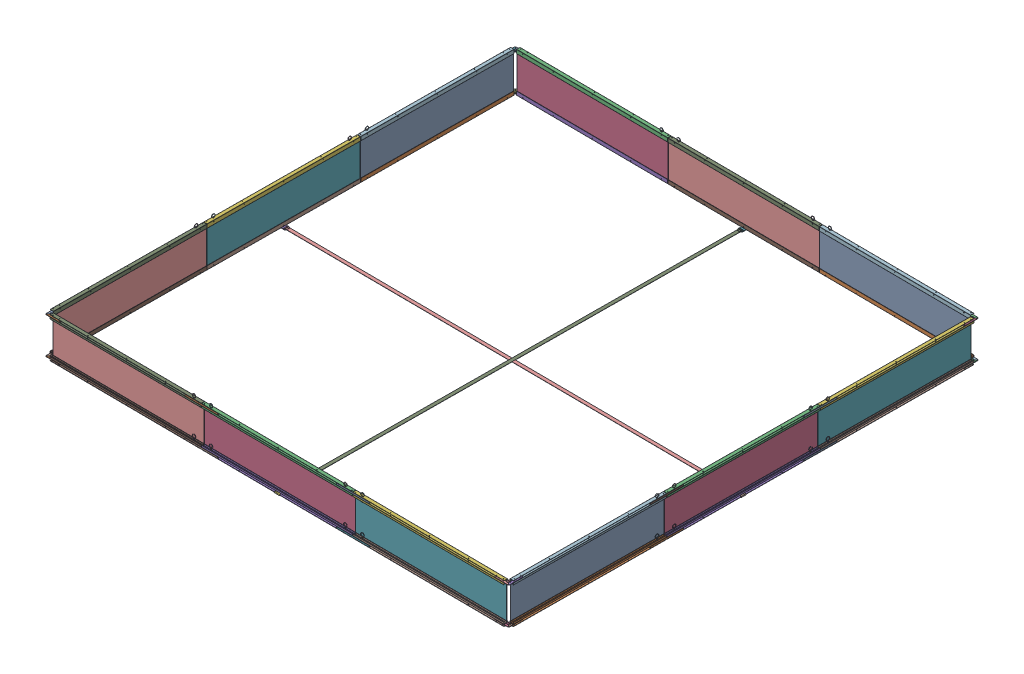
SolidWorks assembly FIELD_RelicRecovery_FTC Field Asm, configuration Default. Lengths in mm.
Overall size (3662.56 340.61 3662.56).
118 component instances, 8 part files, 0 mates.
Components (placement in the parent):
- FIELD_RelicRecovery_Corner Knife Hinge half-1: FIELD_RelicRecovery_Corner Knife Hinge half [Default] at (287.0747 134.4952 780.9902) x (-0.007115 0 0.999975) z (0.999975 0 0.007115) size (108.93 5.01 35.86)
- FIELD_RelicRecovery_Corner Knife Hinge half_DefaultSM-FLAT-PATTERN-1: FIELD_RelicRecovery_Corner Knife Hinge half_DefaultSM-FLAT-PATTERN [Default] at (348.7346 132.3362 843.5339) x (-0.999975 0 -0.007115) z (0.007115 0 -0.999975) size (108.93 5.01 35.86)
- FIELD_RelicRecovery_Corner Knife Hinge half_DefaultSM-FLAT-PATTERN-2: FIELD_RelicRecovery_Corner Knife Hinge half_DefaultSM-FLAT-PATTERN [Default] at (3867.9545 131.9552 -2749.2903) x (0.999975 0 0.007115) z (-0.007115 0 0.999975) size (108.93 5.01 35.86)
- FIELD_RelicRecovery_Corner Knife Hinge half-2: FIELD_RelicRecovery_Corner Knife Hinge half [Default] at (3929.6145 134.1142 -2686.7466) x (0.007115 0 -0.999975) z (-0.999975 0 -0.007115) size (108.93 5.01 35.86)
- FIELD_RelicRecovery_NewStrapClip-1: FIELD_RelicRecovery_NewStrapClip [Default] at (290.995 -150.588 -965.8349) x (-0.007115 0 0.999975) z (-0.999975 0 -0.007115) size (38.1 7.37 60.83)
- FIELD_RelicRecovery_Rail Final Asm-1: FIELD_RelicRecovery_Rail Final Asm [Default] at (207.932 -93.3892 -853.6445) x (0.007115 0 -0.999975) z (0.999975 0 0.007115) size (1185.42 310.9 27.05)
  - FIELD_RelicRecovery_NewRail-1: FIELD_RelicRecovery_NewRail [Default] at (-479.9559 232.0754 95.5976) size (1185.42 29.72 27.05)
  - FIELD_RelicRecovery_New FTC Side Glass-1: FIELD_RelicRecovery_New FTC Side Glass [Default] at (112.7531 85.1364 102.7604) size (1185.42 270.76 3)
  - FIELD_RelicRecovery_NewRail-2: FIELD_RelicRecovery_NewRail [Default] at (705.4621 -61.8026 95.5976) x (-1 0 0) z (0 0 1) size (1185.42 29.72 27.05)
- FIELD_RelicRecovery_Rail Final Asm-2: FIELD_RelicRecovery_Rail Final Asm [Default] at (1019.0407 -93.2622 939.0773) x (-0.999975 0 -0.007115) z (0.007115 0 -0.999975) size (1185.42 310.9 27.05)
  - FIELD_RelicRecovery_NewRail-1: FIELD_RelicRecovery_NewRail [Default] at (-479.9559 232.0754 95.5976) size (1185.42 29.72 27.05)
  - FIELD_RelicRecovery_New FTC Side Glass-1: FIELD_RelicRecovery_New FTC Side Glass [Default] at (112.7531 85.1364 102.7604) size (1185.42 270.76 3)
  - FIELD_RelicRecovery_NewRail-2: FIELD_RelicRecovery_NewRail [Default] at (705.4621 -61.8026 95.5976) x (-1 0 0) z (0 0 1) size (1185.42 29.72 27.05)
- FIELD_RelicRecovery_Rail Final Asm-3: FIELD_RelicRecovery_Rail Final Asm [Default] at (216.3891 -93.3892 -2042.1821) x (0.007115 0 -0.999975) z (0.999975 0 0.007115) size (1185.42 310.9 27.05)
  - FIELD_RelicRecovery_NewRail-1: FIELD_RelicRecovery_NewRail [Default] at (-479.9559 232.0754 95.5976) size (1185.42 29.72 27.05)
  - FIELD_RelicRecovery_New FTC Side Glass-1: FIELD_RelicRecovery_New FTC Side Glass [Default] at (112.7531 85.1364 102.7604) size (1185.42 270.76 3)
  - FIELD_RelicRecovery_NewRail-2: FIELD_RelicRecovery_NewRail [Default] at (705.4621 -61.8026 95.5976) x (-1 0 0) z (0 0 1) size (1185.42 29.72 27.05)
- FIELD_RelicRecovery_Rail Final Asm-4: FIELD_RelicRecovery_Rail Final Asm [Default] at (2207.5782 -93.2622 947.5344) x (-0.999975 0 -0.007115) z (0.007115 0 -0.999975) size (1185.42 310.9 27.05)
  - FIELD_RelicRecovery_NewRail-1: FIELD_RelicRecovery_NewRail [Default] at (-479.9559 232.0754 95.5976) size (1185.42 29.72 27.05)
  - FIELD_RelicRecovery_New FTC Side Glass-1: FIELD_RelicRecovery_New FTC Side Glass [Default] at (112.7531 85.1364 102.7604) size (1185.42 270.76 3)
  - FIELD_RelicRecovery_NewRail-2: FIELD_RelicRecovery_NewRail [Default] at (705.4621 -61.8026 95.5976) x (-1 0 0) z (0 0 1) size (1185.42 29.72 27.05)
- FIELD_RelicRecovery_Rail Final Asm-5: FIELD_RelicRecovery_Rail Final Asm [Default] at (3396.1157 -93.2622 955.9914) x (-0.999975 0 -0.007115) z (0.007115 0 -0.999975) size (1185.42 310.9 27.05)
  - FIELD_RelicRecovery_NewRail-1: FIELD_RelicRecovery_NewRail [Default] at (-479.9559 232.0754 95.5976) size (1185.42 29.72 27.05)
  - FIELD_RelicRecovery_New FTC Side Glass-1: FIELD_RelicRecovery_New FTC Side Glass [Default] at (112.7531 85.1364 102.7604) size (1185.42 270.76 3)
  - FIELD_RelicRecovery_NewRail-2: FIELD_RelicRecovery_NewRail [Default] at (705.4621 -61.8026 95.5976) x (-1 0 0) z (0 0 1) size (1185.42 29.72 27.05)
- FIELD_RelicRecovery_Rail Final Asm-6: FIELD_RelicRecovery_Rail Final Asm [Default] at (199.475 -93.3892 334.893) x (0.007115 0 -0.999975) z (0.999975 0 0.007115) size (1185.42 310.9 27.05)
  - FIELD_RelicRecovery_NewRail-1: FIELD_RelicRecovery_NewRail [Default] at (-479.9559 232.0754 95.5976) size (1185.42 29.72 27.05)
  - FIELD_RelicRecovery_New FTC Side Glass-1: FIELD_RelicRecovery_New FTC Side Glass [Default] at (112.7531 85.1364 102.7604) size (1185.42 270.76 3)
  - FIELD_RelicRecovery_NewRail-2: FIELD_RelicRecovery_NewRail [Default] at (705.4621 -61.8026 95.5976) x (-1 0 0) z (0 0 1) size (1185.42 29.72 27.05)
- FIELD_RelicRecovery_Rail Final Asm-7: FIELD_RelicRecovery_Rail Final Asm [Default] at (4000.3001 -93.2622 136.4257) x (-0.007115 0 0.999975) z (-0.999975 0 -0.007115) size (1185.42 310.9 27.05)
  - FIELD_RelicRecovery_NewRail-1: FIELD_RelicRecovery_NewRail [Default] at (-479.9559 232.0754 95.5976) size (1185.42 29.72 27.05)
  - FIELD_RelicRecovery_New FTC Side Glass-1: FIELD_RelicRecovery_New FTC Side Glass [Default] at (112.7531 85.1364 102.7604) size (1185.42 270.76 3)
  - FIELD_RelicRecovery_NewRail-2: FIELD_RelicRecovery_NewRail [Default] at (705.4621 -61.8026 95.5976) x (-1 0 0) z (0 0 1) size (1185.42 29.72 27.05)
- FIELD_RelicRecovery_Rail Final Asm-8: FIELD_RelicRecovery_Rail Final Asm [Default] at (4008.7571 -93.5162 -1052.1118) x (-0.007115 0 0.999975) z (-0.999975 0 -0.007115) size (1185.42 310.9 27.05)
  - FIELD_RelicRecovery_NewRail-1: FIELD_RelicRecovery_NewRail [Default] at (-479.9559 232.0754 95.5976) size (1185.42 29.72 27.05)
  - FIELD_RelicRecovery_New FTC Side Glass-1: FIELD_RelicRecovery_New FTC Side Glass [Default] at (112.7531 85.1364 102.7604) size (1185.42 270.76 3)
  - FIELD_RelicRecovery_NewRail-2: FIELD_RelicRecovery_NewRail [Default] at (705.4621 -61.8026 95.5976) x (-1 0 0) z (0 0 1) size (1185.42 29.72 27.05)
- FIELD_RelicRecovery_Rail Final Asm-9: FIELD_RelicRecovery_Rail Final Asm [Default] at (4017.2141 -93.7702 -2240.6493) x (-0.007115 0 0.999975) z (-0.999975 0 -0.007115) size (1185.42 310.9 27.05)
  - FIELD_RelicRecovery_NewRail-1: FIELD_RelicRecovery_NewRail [Default] at (-479.9559 232.0754 95.5976) size (1185.42 29.72 27.05)
  - FIELD_RelicRecovery_New FTC Side Glass-1: FIELD_RelicRecovery_New FTC Side Glass [Default] at (112.7531 85.1364 102.7604) size (1185.42 270.76 3)
  - FIELD_RelicRecovery_NewRail-2: FIELD_RelicRecovery_NewRail [Default] at (705.4621 -61.8026 95.5976) x (-1 0 0) z (0 0 1) size (1185.42 29.72 27.05)
- FIELD_RelicRecovery_Rail Final Asm-10: FIELD_RelicRecovery_Rail Final Asm [Default] at (2009.1109 -93.3892 -2853.2907) x (0.999975 0 0.007115) z (-0.007115 0 0.999975) size (1185.42 310.9 27.05)
  - FIELD_RelicRecovery_NewRail-1: FIELD_RelicRecovery_NewRail [Default] at (-479.9559 232.0754 95.5976) size (1185.42 29.72 27.05)
  - FIELD_RelicRecovery_New FTC Side Glass-1: FIELD_RelicRecovery_New FTC Side Glass [Default] at (112.7531 85.1364 102.7604) size (1185.42 270.76 3)
  - FIELD_RelicRecovery_NewRail-2: FIELD_RelicRecovery_NewRail [Default] at (705.4621 -61.8026 95.5976) x (-1 0 0) z (0 0 1) size (1185.42 29.72 27.05)
- FIELD_RelicRecovery_Rail Final Asm-11: FIELD_RelicRecovery_Rail Final Asm [Default] at (3197.6485 -93.6432 -2844.8337) x (0.999975 0 0.007115) z (-0.007115 0 0.999975) size (1185.42 310.9 27.05)
  - FIELD_RelicRecovery_NewRail-1: FIELD_RelicRecovery_NewRail [Default] at (-479.9559 232.0754 95.5976) size (1185.42 29.72 27.05)
  - FIELD_RelicRecovery_New FTC Side Glass-1: FIELD_RelicRecovery_New FTC Side Glass [Default] at (112.7531 85.1364 102.7604) size (1185.42 270.76 3)
  - FIELD_RelicRecovery_NewRail-2: FIELD_RelicRecovery_NewRail [Default] at (705.4621 -61.8026 95.5976) x (-1 0 0) z (0 0 1) size (1185.42 29.72 27.05)
- FIELD_RelicRecovery_Rail Final Asm-12: FIELD_RelicRecovery_Rail Final Asm [Default] at (820.5734 -93.3892 -2861.7477) x (0.999975 0 0.007115) z (-0.007115 0 0.999975) size (1185.42 310.9 27.05)
  - FIELD_RelicRecovery_NewRail-1: FIELD_RelicRecovery_NewRail [Default] at (-479.9559 232.0754 95.5976) size (1185.42 29.72 27.05)
  - FIELD_RelicRecovery_New FTC Side Glass-1: FIELD_RelicRecovery_New FTC Side Glass [Default] at (112.7531 85.1364 102.7604) size (1185.42 270.76 3)
  - FIELD_RelicRecovery_NewRail-2: FIELD_RelicRecovery_NewRail [Default] at (705.4621 -61.8026 95.5976) x (-1 0 0) z (0 0 1) size (1185.42 29.72 27.05)
- FIELD_RelicRecovery_NewStrapClip-2: FIELD_RelicRecovery_NewStrapClip [Default] at (2095.4386 -150.461 864.4718) x (0.999975 0 0.007115) z (-0.007115 0 0.999975) size (38.1 7.37 60.83)
- FIELD_RelicRecovery_NewStrapClip-3: FIELD_RelicRecovery_NewStrapClip [Default] at (2121.3013 -150.588 -2770.2278) x (-0.999975 0 -0.007115) z (0.007115 0 -0.999975) size (38.1 7.37 60.83)
- FIELD_RelicRecovery_NewStrapClip-4: FIELD_RelicRecovery_NewStrapClip [Default] at (3925.6945 -150.715 -939.9722) x (0.007115 0 -0.999975) z (0.999975 0 0.007115) size (38.1 7.37 60.83)
- FIELD_RelicRecovery_Corner Knife Hinge half-3: FIELD_RelicRecovery_Corner Knife Hinge half [Default] at (311.9325 -151.0008 -2712.4881) x (0.007115 0 -0.999975) z (0.999975 0 0.007115) size (108.93 5.01 35.86)
- FIELD_RelicRecovery_Corner Knife Hinge half-4: FIELD_RelicRecovery_Corner Knife Hinge half [Default] at (3842.213 134.6222 868.3917) x (0.999975 0 0.007115) z (0.007115 0 -0.999975) size (108.93 5.01 35.86)
- FIELD_RelicRecovery_Corner Knife Hinge half-5: FIELD_RelicRecovery_Corner Knife Hinge half [Default] at (3904.7567 -150.7468 806.7318) x (-0.007115 0 0.999975) z (-0.999975 0 -0.007115) size (108.93 5.01 35.86)
- FIELD_RelicRecovery_Corner Knife Hinge half-6: FIELD_RelicRecovery_Corner Knife Hinge half [Default] at (3867.9545 -151.2548 -2749.2903) x (0.999975 0 0.007115) z (-0.007115 0 0.999975) size (108.93 5.01 35.86)
- FIELD_RelicRecovery_Corner Knife Hinge half-7: FIELD_RelicRecovery_Corner Knife Hinge half [Default] at (374.4762 134.3682 -2774.1481) x (-0.999975 0 -0.007115) z (-0.007115 0 0.999975) size (108.93 5.01 35.86)
- FIELD_RelicRecovery_Corner Knife Hinge half-8: FIELD_RelicRecovery_Corner Knife Hinge half [Default] at (348.7346 -150.8738 843.5339) x (-0.999975 0 -0.007115) z (0.007115 0 -0.999975) size (108.93 5.01 35.86)
- FIELD_RelicRecovery_Corner Knife Hinge half_DefaultSM-FLAT-PATTERN-3: FIELD_RelicRecovery_Corner Knife Hinge half_DefaultSM-FLAT-PATTERN [Default] at (3929.6145 -149.0958 -2686.7466) x (0.007115 0 -0.999975) z (-0.999975 0 -0.007115) size (108.93 5.01 35.86)
- FIELD_RelicRecovery_Corner Knife Hinge half_DefaultSM-FLAT-PATTERN-4: FIELD_RelicRecovery_Corner Knife Hinge half_DefaultSM-FLAT-PATTERN [Default] at (3842.213 -148.5878 868.3917) x (0.999975 0 0.007115) z (0.007115 0 -0.999975) size (108.93 5.01 35.86)
- FIELD_RelicRecovery_Corner Knife Hinge half_DefaultSM-FLAT-PATTERN-5: FIELD_RelicRecovery_Corner Knife Hinge half_DefaultSM-FLAT-PATTERN [Default] at (3904.7567 132.3362 806.7318) x (-0.007115 0 0.999975) z (-0.999975 0 -0.007115) size (108.93 5.01 35.86)
- FIELD_RelicRecovery_Corner Knife Hinge half_DefaultSM-FLAT-PATTERN-6: FIELD_RelicRecovery_Corner Knife Hinge half_DefaultSM-FLAT-PATTERN [Default] at (374.4762 -148.8418 -2774.1481) x (-0.999975 0 -0.007115) z (-0.007115 0 0.999975) size (108.93 5.01 35.86)
- FIELD_RelicRecovery_Corner Knife Hinge half_DefaultSM-FLAT-PATTERN-7: FIELD_RelicRecovery_Corner Knife Hinge half_DefaultSM-FLAT-PATTERN [Default] at (311.9325 132.2092 -2712.4881) x (0.007115 0 -0.999975) z (0.999975 0 0.007115) size (108.93 5.01 35.86)
- FIELD_RelicRecovery_Corner Knife Hinge half_DefaultSM-FLAT-PATTERN-8: FIELD_RelicRecovery_Corner Knife Hinge half_DefaultSM-FLAT-PATTERN [Default] at (287.0747 -148.7148 780.9902) x (-0.007115 0 0.999975) z (0.999975 0 0.007115) size (108.93 5.01 35.86)
- FIELD_RelicRecovery_Strap-1: FIELD_RelicRecovery_Strap [Default] at (2083.1795 -162.1133 802.4705) x (0.007115 0 -0.999975) z (0.999975 0 0.007115) size (3547.87 7.54 25.4)
- FIELD_RelicRecovery_Strap-2: FIELD_RelicRecovery_Strap [Default] at (352.9963 -162.2403 -978.0941) x (0.999975 0 0.007115) z (-0.007115 0 0.999975) size (3547.87 7.54 25.4)
- FIELD_RelicRecovery_SAPA IAH-821-1: FIELD_RelicRecovery_SAPA IAH-821 [Default] at (3913.8607 138.6862 -472.7354) x (0.999975 0 0.007115) z (-0.007115 0 0.999975) size (19.05 12.7 254)
- FIELD_RelicRecovery_SAPA IAH-821-2: FIELD_RelicRecovery_SAPA IAH-821 [Default] at (3922.3177 138.4322 -1661.2729) x (0.999975 0 0.007115) z (-0.007115 0 0.999975) size (19.05 12.7 254)
- FIELD_RelicRecovery_SAPA IAH-821-3: FIELD_RelicRecovery_SAPA IAH-821 [Default] at (2816.7393 138.6862 861.095) x (0.007115 0 -0.999975) z (-0.999975 0 -0.007115) size (19.05 12.7 254)
- FIELD_RelicRecovery_SAPA IAH-821-4: FIELD_RelicRecovery_SAPA IAH-821 [Default] at (1374.2082 138.6862 850.8307) x (0.007115 0 -0.999975) z (0.999975 0 0.007115) size (19.05 12.7 254)
- FIELD_RelicRecovery_SAPA IAH-821-5: FIELD_RelicRecovery_SAPA IAH-821 [Default] at (296.1787 138.8132 -498.477) x (0.999975 0 0.007115) z (-0.007115 0 0.999975) size (19.05 12.7 254)
- FIELD_RelicRecovery_SAPA IAH-821-6: FIELD_RelicRecovery_SAPA IAH-821 [Default] at (304.6357 138.5592 -1687.0145) x (0.999975 0 0.007115) z (-0.007115 0 0.999975) size (19.05 12.7 254)
- FIELD_RelicRecovery_SAPA IAH-821-7: FIELD_RelicRecovery_SAPA IAH-821 [Default] at (1399.9498 138.8132 -2766.8513) x (0.007115 0 -0.999975) z (0.999975 0 0.007115) size (19.05 12.7 254)
- FIELD_RelicRecovery_SAPA IAH-821-8: FIELD_RelicRecovery_SAPA IAH-821 [Default] at (2842.4809 138.5592 -2756.587) x (-0.007115 0 0.999975) z (-0.999975 0 -0.007115) size (19.05 12.7 254)
- FIELD_RelicRecovery_SAPA IAH-821-9: FIELD_RelicRecovery_SAPA IAH-821 [Default] at (2816.7393 -155.4458 861.095) x (0.007115 0 -0.999975) z (-0.999975 0 -0.007115) size (19.05 12.7 254)
- FIELD_RelicRecovery_SAPA IAH-821-10: FIELD_RelicRecovery_SAPA IAH-821 [Default] at (1374.2082 -155.4458 850.8307) x (0.007115 0 -0.999975) z (0.999975 0 0.007115) size (19.05 12.7 254)
- FIELD_RelicRecovery_SAPA IAH-821-11: FIELD_RelicRecovery_SAPA IAH-821 [Default] at (296.1787 -155.3188 -498.477) x (0.999975 0 0.007115) z (-0.007115 0 0.999975) size (19.05 12.7 254)
- FIELD_RelicRecovery_SAPA IAH-821-12: FIELD_RelicRecovery_SAPA IAH-821 [Default] at (304.6357 -155.5728 -1687.0145) x (0.999975 0 0.007115) z (-0.007115 0 0.999975) size (19.05 12.7 254)
- FIELD_RelicRecovery_SAPA IAH-821-13: FIELD_RelicRecovery_SAPA IAH-821 [Default] at (1399.9498 -155.3188 -2766.8513) x (0.007115 0 -0.999975) z (0.999975 0 0.007115) size (19.05 12.7 254)
- FIELD_RelicRecovery_SAPA IAH-821-14: FIELD_RelicRecovery_SAPA IAH-821 [Default] at (2842.4809 -155.5728 -2756.587) x (-0.007115 0 0.999975) z (-0.999975 0 -0.007115) size (19.05 12.7 254)
- FIELD_RelicRecovery_SAPA IAH-821-15: FIELD_RelicRecovery_SAPA IAH-821 [Default] at (3922.3177 -155.6998 -1661.2729) x (0.999975 0 0.007115) z (-0.007115 0 0.999975) size (19.05 12.7 254)
- FIELD_RelicRecovery_SAPA IAH-821-16: FIELD_RelicRecovery_SAPA IAH-821 [Default] at (3913.8607 -155.4458 -472.7354) x (0.999975 0 0.007115) z (-0.007115 0 0.999975) size (19.05 12.7 254)
- FIELD_RelicRecovery_98404A013_98404A013-1: FIELD_RelicRecovery_98404A013_98404A013 [Default] at (2648.6838 130.4496 -2757.966) x (0 1 0) z (0 0 1) size (65.09 26.92 4.76)
- FIELD_RelicRecovery_98404A013_98404A013-2: FIELD_RelicRecovery_98404A013_98404A013 [Default] at (2782.2844 -142.5299 -2757.0153) x (0 1 0) z (0 0 1) size (65.09 26.92 4.76)
- FIELD_RelicRecovery_98404A013_98404A013-3: FIELD_RelicRecovery_98404A013_98404A013 [Default] at (2648.6838 -142.2759 -2757.966) x (0 1 0) z (0 0 1) size (65.09 26.92 4.76)
- FIELD_RelicRecovery_98404A013_98404A013-4: FIELD_RelicRecovery_98404A013_98404A013 [Default] at (2782.2844 130.1956 -2757.0153) x (0 1 0) z (0 0 1) size (65.09 26.92 4.76)
- FIELD_RelicRecovery_98404A013_98404A013-5: FIELD_RelicRecovery_98404A013_98404A013 [Default] at (1593.7469 -142.2759 -2765.4724) x (0 1 0) z (0 0 1) size (65.09 26.92 4.76)
- FIELD_RelicRecovery_98404A013_98404A013-6: FIELD_RelicRecovery_98404A013_98404A013 [Default] at (1460.1463 128.9256 -2766.423) x (0 1 0) z (0 0 1) size (65.09 26.92 4.76)
- FIELD_RelicRecovery_98404A013_98404A013-7: FIELD_RelicRecovery_98404A013_98404A013 [Default] at (1460.1463 -142.2759 -2766.423) x (0 1 0) z (0 0 1) size (65.09 26.92 4.76)
- FIELD_RelicRecovery_98404A013_98404A013-8: FIELD_RelicRecovery_98404A013_98404A013 [Default] at (1593.7469 130.4496 -2765.4724) x (0 1 0) z (0 0 1) size (65.09 26.92 4.76)
- FIELD_RelicRecovery_98404A013_98404A013-9: FIELD_RelicRecovery_98404A013_98404A013 [Default] at (303.2568 130.4496 -1493.2174) x (0 1 0) z (1 0 0) size (65.09 26.92 4.76)
- FIELD_RelicRecovery_98404A013_98404A013-10: FIELD_RelicRecovery_98404A013_98404A013 [Default] at (1568.0053 130.4496 852.2096) x (0 1 0) z (0 0 -1) size (65.09 26.92 4.76)
- FIELD_RelicRecovery_98404A013_98404A013-11: FIELD_RelicRecovery_98404A013_98404A013 [Default] at (3913.4324 130.4496 -412.5389) x (0 1 0) z (-1 0 0) size (65.09 26.92 4.76)
- FIELD_RelicRecovery_98404A013_98404A013-12: FIELD_RelicRecovery_98404A013_98404A013 [Default] at (304.2074 -142.5299 -1626.818) x (0 1 0) z (1 0 0) size (65.09 26.92 4.76)
- FIELD_RelicRecovery_98404A013_98404A013-13: FIELD_RelicRecovery_98404A013_98404A013 [Default] at (1434.4047 -142.5299 851.259) x (0 1 0) z (0 0 -1) size (65.09 26.92 4.76)
- FIELD_RelicRecovery_98404A013_98404A013-14: FIELD_RelicRecovery_98404A013_98404A013 [Default] at (3912.4817 -142.5299 -278.9383) x (0 1 0) z (-1 0 0) size (65.09 26.92 4.76)
- FIELD_RelicRecovery_98404A013_98404A013-15: FIELD_RelicRecovery_98404A013_98404A013 [Default] at (303.2568 -142.2759 -1493.2174) x (0 1 0) z (1 0 0) size (65.09 26.92 4.76)
- FIELD_RelicRecovery_98404A013_98404A013-16: FIELD_RelicRecovery_98404A013_98404A013 [Default] at (1568.0053 -142.2759 852.2096) x (0 1 0) z (0 0 -1) size (65.09 26.92 4.76)
- FIELD_RelicRecovery_98404A013_98404A013-17: FIELD_RelicRecovery_98404A013_98404A013 [Default] at (3913.4324 -142.2759 -412.5389) x (0 1 0) z (-1 0 0) size (65.09 26.92 4.76)
- FIELD_RelicRecovery_98404A013_98404A013-18: FIELD_RelicRecovery_98404A013_98404A013 [Default] at (304.2074 130.1956 -1626.818) x (0 1 0) z (1 0 0) size (65.09 26.92 4.76)
- FIELD_RelicRecovery_98404A013_98404A013-19: FIELD_RelicRecovery_98404A013_98404A013 [Default] at (1434.4047 130.1956 851.259) x (0 1 0) z (0 0 -1) size (65.09 26.92 4.76)
- FIELD_RelicRecovery_98404A013_98404A013-20: FIELD_RelicRecovery_98404A013_98404A013 [Default] at (3912.4817 130.1956 -278.9383) x (0 1 0) z (-1 0 0) size (65.09 26.92 4.76)
- FIELD_RelicRecovery_98404A013_98404A013-21: FIELD_RelicRecovery_98404A013_98404A013 [Default] at (294.7997 128.9256 -304.6799) x (0 1 0) z (1 0 0) size (65.09 26.92 4.76)
- FIELD_RelicRecovery_98404A013_98404A013-22: FIELD_RelicRecovery_98404A013_98404A013 [Default] at (2756.5428 128.9256 860.6667) x (0 1 0) z (0 0 -1) size (65.09 26.92 4.76)
- FIELD_RelicRecovery_98404A013_98404A013-23: FIELD_RelicRecovery_98404A013_98404A013 [Default] at (3921.8894 128.9256 -1601.0764) x (0 1 0) z (-1 0 0) size (65.09 26.92 4.76)
- FIELD_RelicRecovery_98404A013_98404A013-24: FIELD_RelicRecovery_98404A013_98404A013 [Default] at (295.7504 -142.2759 -438.2805) x (0 1 0) z (1 0 0) size (65.09 26.92 4.76)
- FIELD_RelicRecovery_98404A013_98404A013-25: FIELD_RelicRecovery_98404A013_98404A013 [Default] at (2622.9422 -142.2759 859.716) x (0 1 0) z (0 0 -1) size (65.09 26.92 4.76)
- FIELD_RelicRecovery_98404A013_98404A013-26: FIELD_RelicRecovery_98404A013_98404A013 [Default] at (3920.9388 -142.2759 -1467.4758) x (0 1 0) z (-1 0 0) size (65.09 26.92 4.76)
- FIELD_RelicRecovery_98404A013_98404A013-27: FIELD_RelicRecovery_98404A013_98404A013 [Default] at (294.7997 -142.2759 -304.6799) x (0 1 0) z (1 0 0) size (65.09 26.92 4.76)
- FIELD_RelicRecovery_98404A013_98404A013-28: FIELD_RelicRecovery_98404A013_98404A013 [Default] at (2756.5428 -142.2759 860.6667) x (0 1 0) z (0 0 -1) size (65.09 26.92 4.76)
- FIELD_RelicRecovery_98404A013_98404A013-29: FIELD_RelicRecovery_98404A013_98404A013 [Default] at (3921.8894 -142.2759 -1601.0764) x (0 1 0) z (-1 0 0) size (65.09 26.92 4.76)
- FIELD_RelicRecovery_98404A013_98404A013-30: FIELD_RelicRecovery_98404A013_98404A013 [Default] at (295.7504 130.4496 -438.2805) x (0 1 0) z (1 0 0) size (65.09 26.92 4.76)
- FIELD_RelicRecovery_98404A013_98404A013-31: FIELD_RelicRecovery_98404A013_98404A013 [Default] at (2622.9422 130.4496 859.716) x (0 1 0) z (0 0 -1) size (65.09 26.92 4.76)
- FIELD_RelicRecovery_98404A013_98404A013-32: FIELD_RelicRecovery_98404A013_98404A013 [Default] at (3920.9388 130.4496 -1467.4758) x (0 1 0) z (-1 0 0) size (65.09 26.92 4.76)
